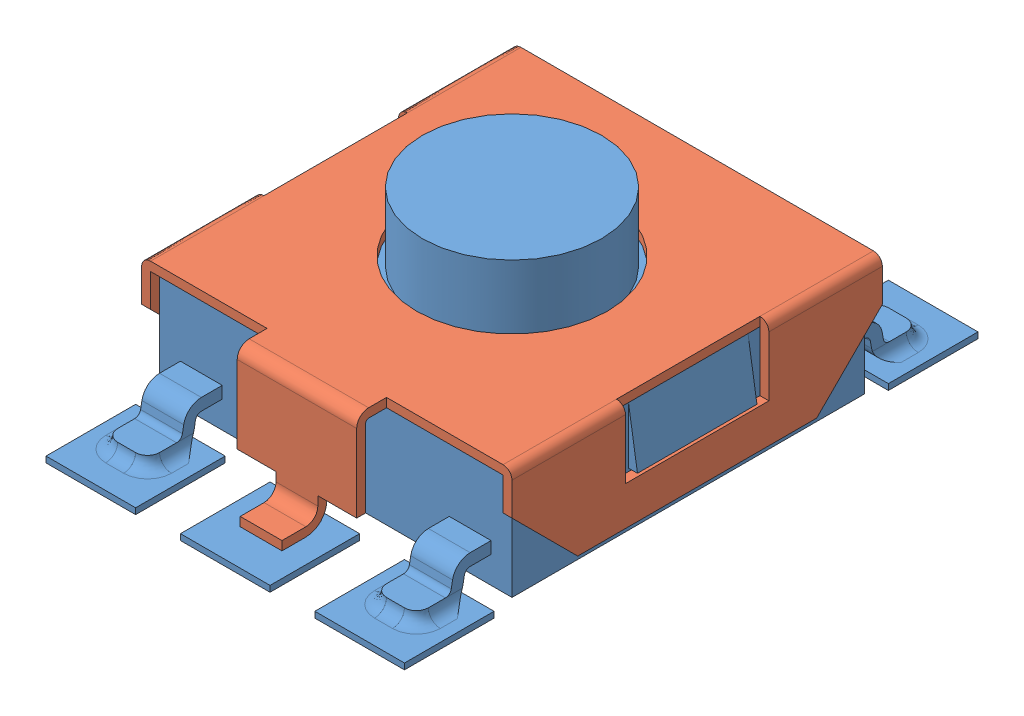
SolidWorks assembly RESET BUTTON, configuration Default. Lengths in mm.
Overall size (6.2 3.1 9.6).
2 component instances, 2 part files, 6 mates.
Components (placement in the parent):
- RESET CORE-1: RESET CORE [Default] at (0 0.1 0) x (-1 0 0) z (0 0 -1) size (6.2 3.1 9.6)
- RESET-1: RESET [Default] at (0 0.1 0) x (0 0 1) z (-1 0 0) size (7.3 2 6.2)
Mates (geometry in assembly coordinates):
- Coincident4: coincident anti-aligned: plane of RESET CORE-1 through (0 0.1 0) normal (0 0 -1); plane of assembly
- Coincident5: coincident anti-aligned: plane of RESET CORE-1 through (0 0.1 0) normal (-1 0 0); plane of assembly through (0 0 0) normal (1 0 0)
- Coincident6: coincident anti-aligned: plane of RESET CORE-1 through (0 0 0) normal (0 -1 0); plane of assembly through (0 0 0) normal (0 1 0)
- Coincident7: coincident aligned: plane of RESET-1 through (0 0.1 0) normal (0 0 1); plane of assembly
- Coincident9: coincident anti-aligned: plane of RESET-1 through (0 0.1 0) normal (-1 0 0); plane of assembly through (0 0 0) normal (1 0 0)
- Coincident10: coincident aligned: plane of RESET CORE-1; plane of RESET-1
